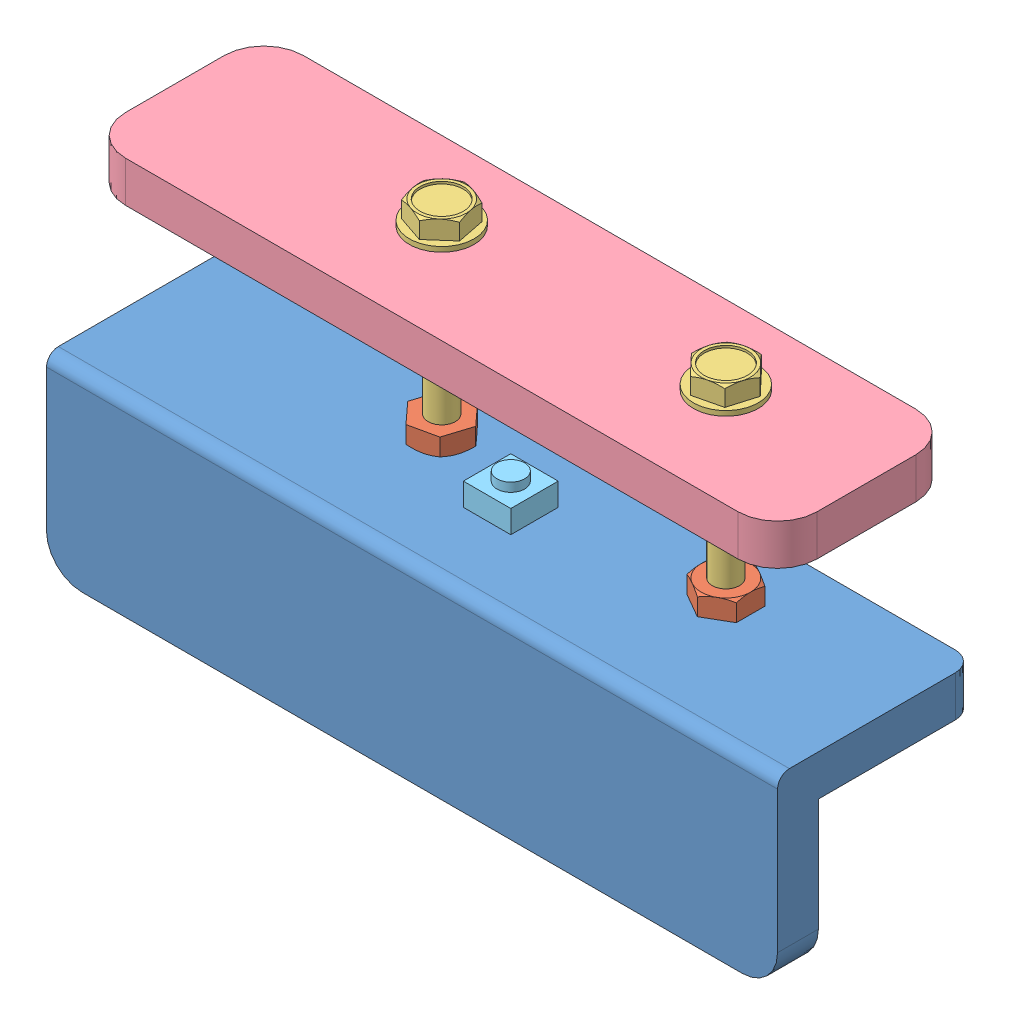
SolidWorks assembly Bumper, configuration Default. Lengths in mm.
Overall size (93.98 51.58 25.4).
11 component instances, 5 part files, 26 mates.
Components (placement in the parent):
- bumperMount-2: bumperMount [Default] at origin size (93.98 24.31 25.4)
- machine screw nut hex_ai-1: machine screw nut hex_ai [MSHXNUT 0.112-40-S-N] at (-11.5062 7.3072 -12.7) x (1 0 0) z (0 -1 0) size (6.35 7.33 2.49)
- machine screw nut hex_ai-2: machine screw nut hex_ai [MSHXNUT 0.112-40-S-N] at (-11.5062 31.3102 -12.7) x (1 0 0) z (0 -1 0) size (6.35 7.33 2.49)
- machine screw nut hex_ai-3: machine screw nut hex_ai [MSHXNUT 0.112-40-S-N] at (25.019 7.3072 -12.7) x (1 0 0) z (0 -1 0) size (6.35 7.33 2.49)
- machine screw nut hex_ai-4: machine screw nut hex_ai [MSHXNUT 0.112-40-S-N] at (25.019 18.1276 -12.7) x (1 0 0) z (0 1 0) size (6.35 7.33 2.49)
- machine screw nut hex_ai-5: machine screw nut hex_ai [MSHXNUT 0.112-40-S-N] at (25.019 33.7994 -12.7) x (0.866025 0 0.5) z (0 1 0) size (6.35 7.33 2.49)
- machine screw nut hex_ai-6: machine screw nut hex_ai [MSHXNUT 0.112-40-S-N] at (-11.5062 15.6384 -12.7) x (0.214941 0 0.976627) z (0 -1 0) size (6.35 7.33 2.49)
- hex washer screw_ai-5: hex washer screw_ai [IN-HWMS 0.138-40x1.25x1-N] at (-11.5062 42.0544 -12.7) x (0 -1 0) z (0.980819 0 -0.194919) size (34.75 8.33 8.33)
- hex washer screw_ai-6: hex washer screw_ai [IN-HWMS 0.138-40x1.25x1-N] at (25.019 42.0544 -12.7) x (0 -1 0) z (-0.725996 0 0.687699) size (34.75 8.33 8.33)
- bumperPlate-1: bumperPlate [Default] at (0 33.7994 -11.3411) x (1 0 0) z (0 1 0) size (88.9 22.86 5.26)
- Button-1: Button [Default] at (146.9508 14.7828 69.858) x (1 0 0) z (0 1 0) size (6.1 6.1 4.06)
Mates (geometry in assembly coordinates):
- Parallel4: parallel anti-aligned: plane of bumperMount-2 through (-46.99 14.7828 -22.7711) normal (0 1 0); plane of hex washer screw_ai-5 through (-11.8478 7.3072 -14.419) normal (0 -1 0)
- Concentric4: concentric anti-aligned: cylinder of machine screw nut hex_ai-1 through (-11.5062 9.7964 -12.7) axis (0 -1 0) radius 1.1303; cylinder of hex washer screw_ai-5 through (-11.5062 67.4544 -12.7) axis (0 1 0) radius 1.7526
- Width3: width anti-aligned: plane of bumperMount-2 through (46.99 9.525 -2.6289) normal (0 0 -1); plane of bumperMount-2 through (-46.99 14.7828 -22.7711) normal (0 0 -1); cylinder of hex washer screw_ai-5 through (-11.5062 67.4544 -12.7) axis (0 1 0) radius 1.7526
- Parallel5: parallel aligned: plane of bumperMount-2 through (-46.99 9.525 -22.7711) normal (0 -1 0); plane of hex washer screw_ai-6 through (26.2243 7.3072 -11.4276) normal (0 -1 0)
- Width4: width anti-aligned: plane of bumperMount-2 through (46.99 9.525 -2.6289) normal (0 0 -1); plane of bumperMount-2 through (-46.99 14.7828 -22.7711) normal (0 0 -1); cylinder of hex washer screw_ai-6 through (25.019 67.4544 -12.7) axis (0 1 0) radius 1.7526
- Concentric5: concentric anti-aligned: cylinder of machine screw nut hex_ai-6 through (-11.5062 18.1276 -12.7) axis (0 -1 0) radius 1.1303; cylinder of hex washer screw_ai-5 through (-11.5062 67.4544 -12.7) axis (0 1 0) radius 1.7526
- Concentric6: concentric aligned: cylinder of machine screw nut hex_ai-4 through (25.019 15.6384 -12.7) axis (0 1 0) radius 1.1303; cylinder of hex washer screw_ai-6 through (25.019 67.4544 -12.7) axis (0 1 0) radius 1.7526
- Concentric7: concentric anti-aligned: cylinder of machine screw nut hex_ai-3 through (25.019 9.7964 -12.7) axis (0 -1 0) radius 1.1303; cylinder of hex washer screw_ai-6 through (25.019 67.4544 -12.7) axis (0 1 0) radius 1.7526
- Parallel6: parallel anti-aligned: plane of bumperMount-2 through (-46.99 14.7828 -22.7711) normal (0 1 0); plane of bumperPlate-1 through (44.45 33.7994 -22.7711) normal (0 -1 0)
- Coincident13: coincident aligned: plane of bumperMount-2 through (-46.99 14.7828 -22.7711) normal (0 0 -1); plane of bumperPlate-1 through (-44.45 39.0572 -22.7711) normal (0 0 -1)
- Width5: width anti-aligned: plane of bumperMount-2 through (46.99 -9.525 2.6289) normal (1 0 0); plane of bumperMount-2 through (-46.99 -9.525 2.6289) normal (-1 0 0); plane of bumperPlate-1 through (-44.45 39.0572 0.0889) normal (-1 0 0); plane of bumperPlate-1 through (44.45 39.0572 0.0889) normal (1 0 0)
- Coincident14: coincident anti-aligned: plane of hex washer screw_ai-5 through (-11.8478 39.0572 -14.419) normal (0 -1 0); plane of bumperPlate-1 through (44.45 39.0572 -22.7711) normal (0 1 0)
- Coincident15: coincident anti-aligned: plane of hex washer screw_ai-6 through (26.2243 39.0572 -11.4276) normal (0 -1 0); plane of bumperPlate-1 through (44.45 39.0572 -22.7711) normal (0 1 0)
- Coincident16: coincident anti-aligned: plane of machine screw nut hex_ai-5 through (19.5197 33.7994 -15.875) normal (0 1 0); plane of bumperPlate-1 through (44.45 33.7994 -22.7711) normal (0 -1 0)
- Concentric9: concentric aligned: cylinder of machine screw nut hex_ai-5 through (25.019 31.3102 -12.7) axis (0 1 0) radius 1.1303; cylinder of hex washer screw_ai-6 through (25.019 67.4544 -12.7) axis (0 1 0) radius 1.7526
- Concentric10: concentric anti-aligned: cylinder of machine screw nut hex_ai-2 through (-11.5062 33.7994 -12.7) axis (0 -1 0) radius 1.1303; cylinder of hex washer screw_ai-5 through (-11.5062 67.4544 -12.7) axis (0 1 0) radius 1.7526
- Coincident17: coincident anti-aligned: plane of machine screw nut hex_ai-2 through (-17.8562 33.7994 -12.7) normal (0 1 0); plane of bumperPlate-1 through (44.45 33.7994 -22.7711) normal (0 -1 0)
- Distance1: distance = 5.842 mm anti-aligned: plane of machine screw nut hex_ai-6 through (-12.8711 15.6384 -18.9016) normal (0 -1 0); plane of machine screw nut hex_ai-1 through (-17.8562 9.7964 -12.7) normal (0 1 0)
- Distance2: distance = 5.842 mm anti-aligned: plane of machine screw nut hex_ai-3 through (18.669 9.7964 -12.7) normal (0 1 0); plane of machine screw nut hex_ai-4 through (18.669 15.6384 -12.7) normal (0 -1 0)
- Coincident20: coincident aligned: plane of machine screw nut hex_ai-1 through (-17.8562 7.3072 -12.7) normal (0 -1 0); plane of hex washer screw_ai-5 through (-11.8478 7.3072 -14.419) normal (0 -1 0)
- Coincident21: coincident aligned: plane of machine screw nut hex_ai-3 through (18.669 7.3072 -12.7) normal (0 -1 0); plane of hex washer screw_ai-6 through (26.2243 7.3072 -11.4276) normal (0 -1 0)
- Coincident22: coincident anti-aligned: plane of bumperMount-2 through (-46.99 14.7828 -22.7711) normal (0 1 0); plane of Button-1 through (3.048 14.7828 -7.0231) normal (0 -1 0)
- Width6: width aligned: plane of Button-1 through (-3.048 17.7038 -13.1191) normal (-1 0 0); plane of Button-1 through (3.048 17.7038 -13.1191) normal (1 0 0); plane of bumperMount-2 through (-46.99 -9.525 2.6289) normal (-1 0 0); plane of bumperMount-2 through (46.99 -9.525 2.6289) normal (1 0 0)
- Width7: width anti-aligned: plane of bumperMount-2 through (-46.99 14.7828 -22.7711) normal (0 0 -1); plane of bumperMount-2 through (46.99 9.525 2.6289) normal (0 0 1); plane of Button-1 through (-3.048 17.7038 -7.0231) normal (0 0 1); plane of Button-1 through (-3.048 17.7038 -13.1191) normal (0 0 -1)
- Distance3: distance = 33.02 mm: cylinder of hex washer screw_ai-5 through (-11.5062 67.4544 -12.7) axis (0 1 0) radius 1.7526; cylinder of hex washer screw_ai-6 through (25.019 67.4544 -12.7) axis (0 1 0) radius 1.7526
- Width10: width aligned: plane of Button-1 through (3.048 17.7038 -13.1191) normal (1 0 0); plane of bumperMount-2 through (46.99 -9.525 2.6289) normal (1 0 0); plane of machine screw nut hex_ai-4 through (28.194 15.6384 -14.5331) normal (1 0 0); plane of machine screw nut hex_ai-4 through (21.844 15.6384 -14.5331) normal (-1 0 0)
